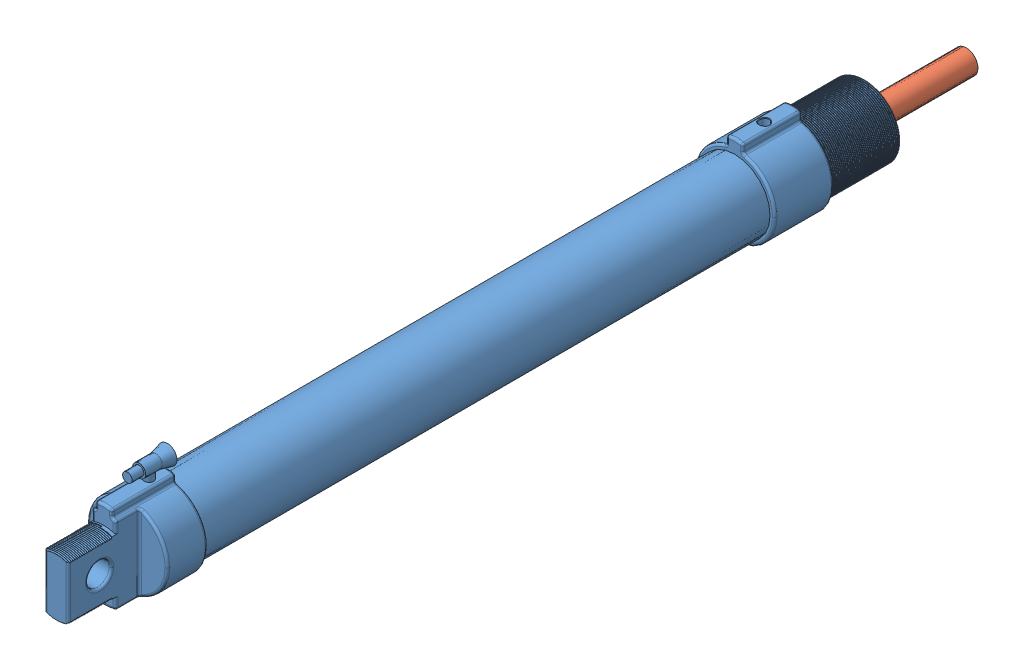
SolidWorks assembly piston-rod, configuration Default. Lengths in mm.
Overall size (42.21 48.74 385.68).
3 component instances, 2 part files, 2 mates.
Components (placement in the parent):
- cylender-1: cylender [Default] at (14.7656 212.3163 308.0608) size (40.07 46.79 343.61)
- Assem1^piston-rod-1: Assem1^piston-rod [Default] at (3.3049 418.3638 129.6317) x (-0.972674 -0.232173 0) z (0 0 1) size (31.76 31.76 337) (virtual)
  - rod-1: rod [Default] at (36.6911 203.0781 380.4291) x (0.254643 -0.967035 0) z (0 0 -1) size (26 26 337)
Mates (geometry in assembly coordinates):
- Concentric1: concentric anti-aligned: cylinder of cylender-1 through (14.7656 212.3163 308.0608) axis (0 0 1) radius 15; cylinder of Assem1^piston-rod-1/rod-1 through (14.7656 212.3163 547.0608) axis (0 0 -1) radius 13
- LimitDistance1: limit distance = 1 mm anti-aligned: plane of cylender-1 through (-1.4264 196.1053 548.0608) normal (0 0 -1); plane of Assem1^piston-rod-1/rod-1 through (14.7656 212.3163 547.0608) normal (0 0 1)
